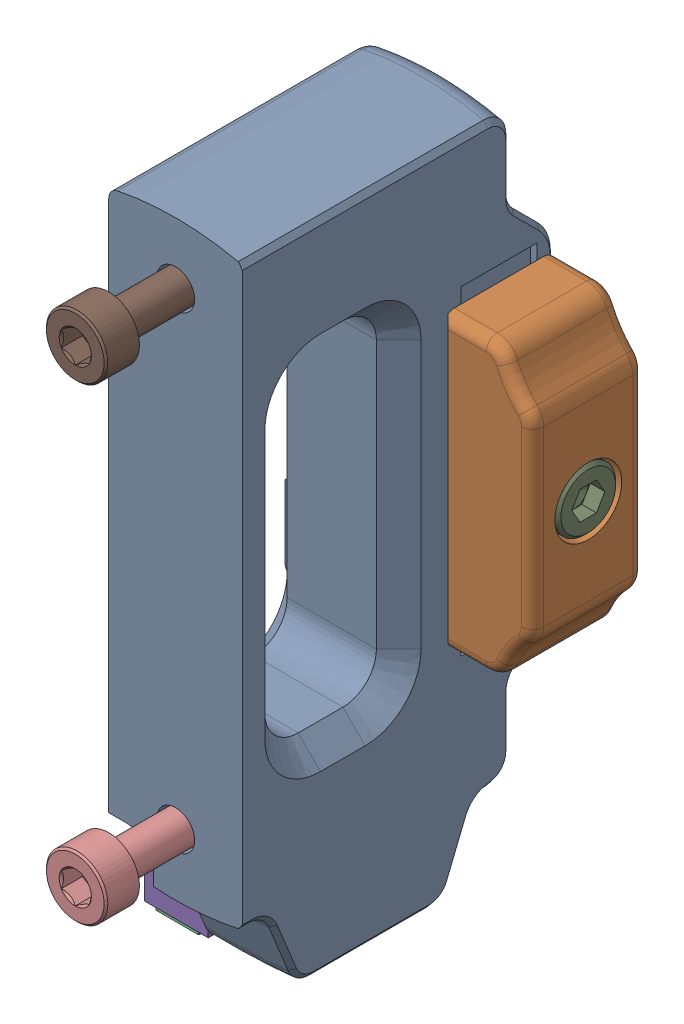
SolidWorks assembly Y Belt Anchor, configuration Default. Lengths in mm.
Overall size (25.6 63.59 37.15).
16 component instances, 9 part files, 0 mates.
Components (placement in the parent):
- Y Belt Anchor-1: Y Belt Anchor [Default] at origin size (18.1 59.67 28)
- Y Belt Clamp-1: Y Belt Clamp [Default] at origin size (8 26 10)
- KW10 Microswitch v2 v1-1: KW10 Microswitch v2 v1 [Default] at (19.4485 -92.5 81.85) x (0 0 1) z (0 -1 0) size (13.18 5.8 12.93)
  - Component2-1: Component2 [Default] at (-0.4015 5 5) x (-1 0 0) z (0 0 1) size (13.18 5.8 12.93)
    - Component3-1: Component3 [Default] at origin size (13.08 3.8 4.39)
      - Component6-1: Component6 [Default] at origin size (13.08 3.8 4.39)
    - Component7-1: Component7 [Default] at origin size (1.2 1.2 3)
    - Component8-1: Component8 [Default] at origin size (12.8 5.8 10.15)
- M3 Threaded Insert (1)-1: M3 Threaded Insert (1) [Default] at (19.578 -49.8414 72.85) x (1 0 0) z (0 0 -1) size (5 5 3.85)
- M3 Threaded Insert (1)-2: M3 Threaded Insert (1) [Default] at (19.578 -91.8414 72.85) x (1 0 0) z (0 0 -1) size (5 5 3.85)
- M3 Threaded Insert (1)-3: M3 Threaded Insert (1) [Default] at (21.728 -70.8414 70) x (0 0 1) z (1 0 0) size (5 5 3.85)
- M3x12 SHCS (2)-1: M3x12 SHCS (2) [Default] at (33.578 -70.8414 70) x (-1 0 0) z (0 1 0) size (15 5.5 5.5)
- M3x30 SHCS (1)-1: M3x30 SHCS (1) [Default] at (19.578 -91.8414 69) x (1 0 0) z (0 0 -1) size (5.5 5.5 33.14)
- M3x30 SHCS (1)-2: M3x30 SHCS (1) [Default] at (19.578 -49.8414 69) x (1 0 0) z (0 0 -1) size (5.5 5.5 33.14)
- M2x10 Self-Tapping Screw-1: M2x10 Self-Tapping Screw [Default] at (21.5485 -99 78.1985) x (0 0 -1) z (1 0 0) size (3.8 3.8 12.09)
- M2x10 Self-Tapping Screw-2: M2x10 Self-Tapping Screw [Default] at (21.5485 -99 84.6985) x (0 0 -1) z (1 0 0) size (3.8 3.8 12.09)
